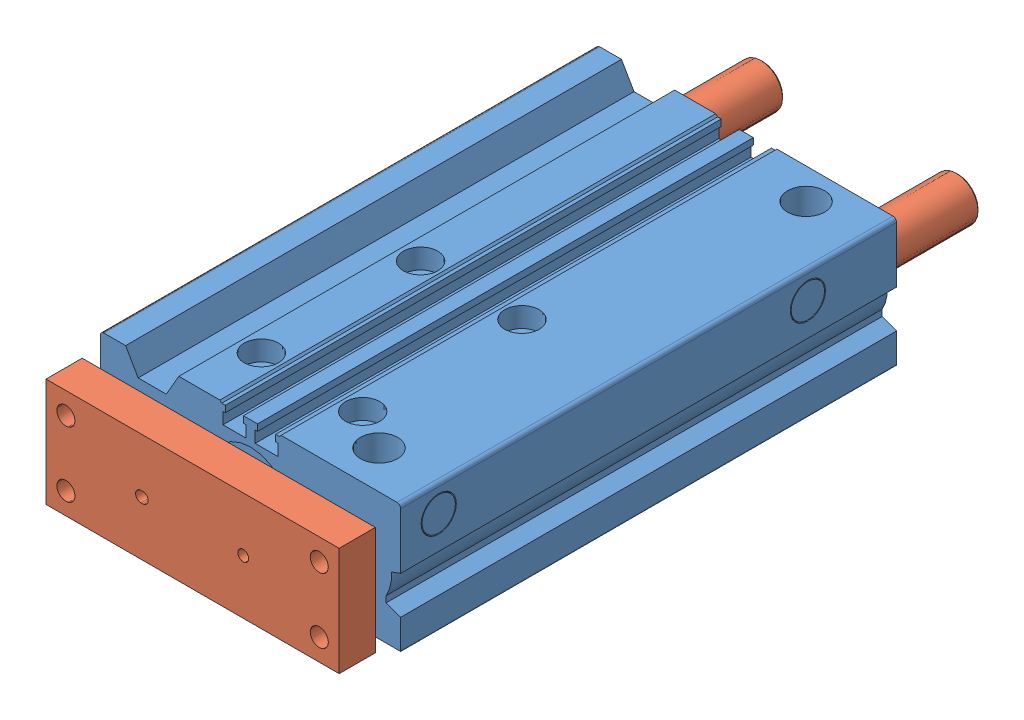
SolidWorks assembly MGPM20N-100, configuration MGPM20N-100. Lengths in mm.
Overall size (83 36 184.5).
2 component instances, 2 part files, 3 mates.
Components (placement in the parent):
- MGPM20N-100_MGPTube-1: MGPM20N-100_MGPTube [20M] at origin size (83 36 137)
- MGPM20N-100_MGPRod-1: MGPM20N-100_MGPRod [20M] at (0 0 -52.5) size (81 30 184.5)
Mates (geometry in assembly coordinates):
- Concentric1: concentric anti-aligned: cylinder of MGPM20N-100_MGPTube-1 through (0 0 -14.2836) axis (0 0 1) radius 5.05; cylinder of MGPM20N-100_MGPRod-1 through (0 0 88.6421) axis (0 0 -1) radius 5
- Parallel1: parallel aligned: plane of MGPM20N-100_MGPRod-1 through (0 0 -52.5) normal (0 1 0); plane of assembly through (0 0 0) normal (0 1 0)
- Coincident1: coincident anti-aligned: plane of MGPM20N-100_MGPTube-1 through (0 0 -52.5) normal (0 0 1); plane of MGPM20N-100_MGPRod-1 through (0 0 -52.5) normal (0 0 -1)
